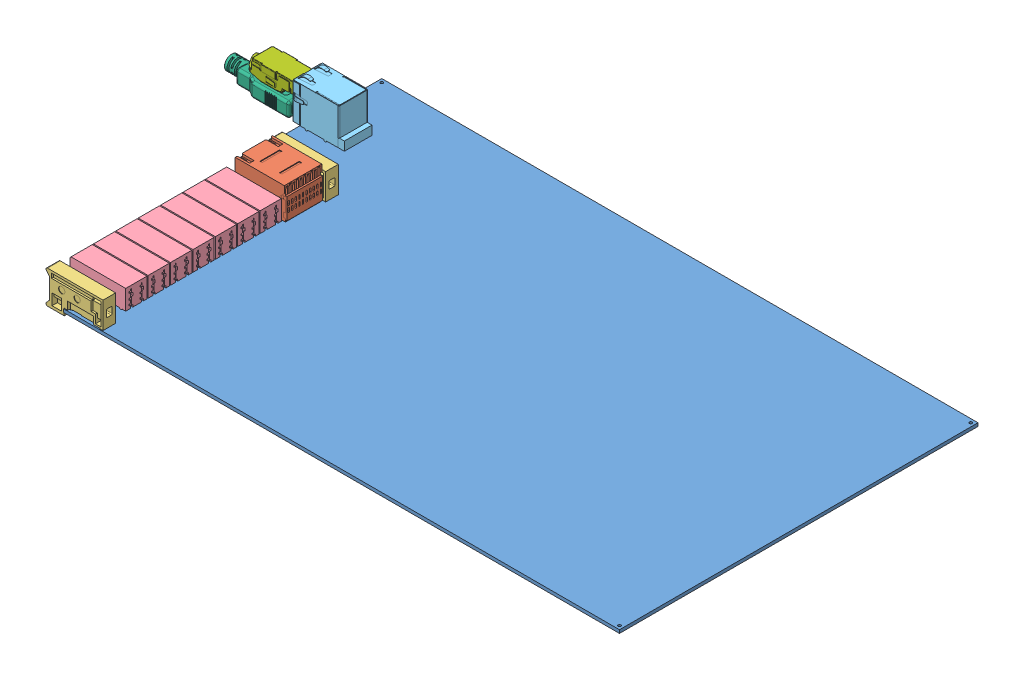
SolidWorks assembly SCT8-Board, configuration Default. Lengths in mm.
Overall size (378.17 27.6 200).
15 component instances, 7 part files, 15 mates.
Components (placement in the parent):
- SCT8-Board-1: SCT8-Board [Default] at origin size (332.58 1.8 200)
- EBTF-4-10-2.0-S-RA-1-2: EBTF-4-10-2.0-S-RA-1 [Default] at (77.38 -2.8 -123.6) x (0 0 1) z (-1 0 0) size (20.9 22.5 28.4)
- EGBF-RA-20-3: EGBF-RA-20 [Default] at (84.045 9.05 -138.2) x (-1 0 0) z (0 0 -1) size (31.8 18.7 7.05)
- EGBF-RA-20-4: EGBF-RA-20 [Default] at (84.045 9.05 -14) x (-1 0 0) z (0 0 -1) size (31.8 18.7 7.05)
- EPTT-2-P-11.5-D-RA-8: EPTT-2-P-11.5-D-RA [Default] at (77.38 -2.6 -31.6) size (31 15.9 11.85)
- EPTT-2-P-11.5-D-RA-9: EPTT-2-P-11.5-D-RA [Default] at (77.38 -2.6 -44.1) size (31 15.9 11.85)
- EPTT-2-P-11.5-D-RA-10: EPTT-2-P-11.5-D-RA [Default] at (77.38 -2.6 -56.6) size (31 15.9 11.85)
- EPTT-2-P-11.5-D-RA-11: EPTT-2-P-11.5-D-RA [Default] at (77.38 -2.6 -69.1) size (31 15.9 11.85)
- EPTT-2-P-11.5-D-RA-12: EPTT-2-P-11.5-D-RA [Default] at (77.38 -2.6 -81.6) size (31 15.9 11.85)
- EPTT-2-P-11.5-D-RA-13: EPTT-2-P-11.5-D-RA [Default] at (77.38 -2.6 -94.1) size (31 15.9 11.85)
- EPTT-2-P-11.5-D-RA-14: EPTT-2-P-11.5-D-RA [Default] at (77.38 -2.6 -106.6) size (31 15.9 11.85)
- RJMG233022610ER-2: RJMG233022610ER [Default] at (59.18 1.8 -171.765) x (0 0 1) z (-1 0 0) size (18.42 26.43 70.66)
  - RJMG233022610ER-1: RJMG233022610ER [Default] at (0 21.08 7.68) size (18.42 26.43 28.81)
  - USB-1: USB [Default] at (0 8.17 25.939) x (0 -1 0) z (0 0 -1) size (8 15.47 51.41)
  - 77404-1: 77404 [Default] at (0 14.29 -2.521) x (1 0 0) z (0 0 -1) size (13.45 10.15 40.2)
Mates (geometry in assembly coordinates):
- Coincident1: coincident: plane of SCT8-Board-1 through (0 1.8 0) normal (0 1 0); plane of EBTF-4-10-2.0-S-RA-1-2 through (95.48 1.8 -113.75) normal (0 -1 0)
- Parallel1: parallel: plane of SCT8-Board-1 through (77.58 -0.001 -10) normal (-1 0 0); plane of EBTF-4-10-2.0-S-RA-1-2 through (77.38 -2.8 -113.15) normal (1 0 0)
- Concentric1: concentric: cylinder of SCT8-Board-1 through (79.08 1.8 -114.4) axis (0 1 0) radius 0.75; line of EBTF-4-10-2.0-S-RA-1-2 through (79.08 0.8936 -114.4) axis (0 -1 0)
- Coincident3: coincident: plane of SCT8-Board-1 through (0 1.8 0) normal (0 1 0); plane of EGBF-RA-20-3 through (80.9 1.8 -141.725) normal (0 -1 0)
- Parallel2: parallel: plane of SCT8-Board-1 through (77.58 -0.001 -10) normal (-1 0 0); plane of EGBF-RA-20-3 through (77.4 1.8 -141.725) normal (1 0 0)
- Concentric2: concentric: cylinder of SCT8-Board-1 through (88.53 1.8 -138.2) axis (0 1 0) radius 1.6; line of EGBF-RA-20-3 through (88.53 18.4179 -138.2) axis (0 -1 0)
- Coincident5: coincident: plane of SCT8-Board-1 through (0 1.8 0) normal (0 1 0); plane of EGBF-RA-20-4 through (80.9 1.8 -17.525) normal (0 -1 0)
- Parallel3: parallel: plane of SCT8-Board-1 through (77.58 -0.001 -10) normal (-1 0 0); plane of EGBF-RA-20-4 through (77.4 1.8 -17.525) normal (1 0 0)
- Concentric3: concentric: cylinder of SCT8-Board-1 through (88.53 1.8 -14) axis (0 1 0) radius 1.6; line of EGBF-RA-20-4 through (88.53 18.4179 -14) axis (0 -1 0)
- Coincident7: coincident: plane of SCT8-Board-1 through (0 1.8 0) normal (0 1 0); plane of EPTT-2-P-11.5-D-RA-8 through (85.92 1.8 -25.675) normal (0 -1 0)
- Parallel4: parallel: plane of SCT8-Board-1 through (77.58 -0.001 -10) normal (-1 0 0); plane of EPTT-2-P-11.5-D-RA-8 through (77.38 -1.3 -25.675) normal (1 0 0)
- Concentric4: concentric: cylinder of SCT8-Board-1 through (81.83 1.8 -31.6) axis (0 1 0) radius 1.1; cylinder of EPTT-2-P-11.5-D-RA-8 through (81.83 -2.1 -31.6) axis (0 1 0) radius 0.875
- Coincident9: coincident: plane of SCT8-Board-1 through (0 1.8 0) normal (0 1 0); plane of RJMG233022610ER-2/RJMG233022610ER-1 through (24.3406 1.8 -274.1678) normal (0 -1 0)
- Parallel5: parallel: plane of SCT8-Board-1 through (55 1.8 -10) normal (-1 0 0); plane of RJMG233022610ER-2/RJMG233022610ER-1 through (48.6096 7.1 -274.1678) normal (1 0 0)
- Concentric5: concentric: cylinder of SCT8-Board-1 through (59.18 1.8 -179.765) axis (0 1 0) radius 0.6; line of RJMG233022610ER-2 through (59.18 3.2443 -179.765) axis (0 -1 0)
